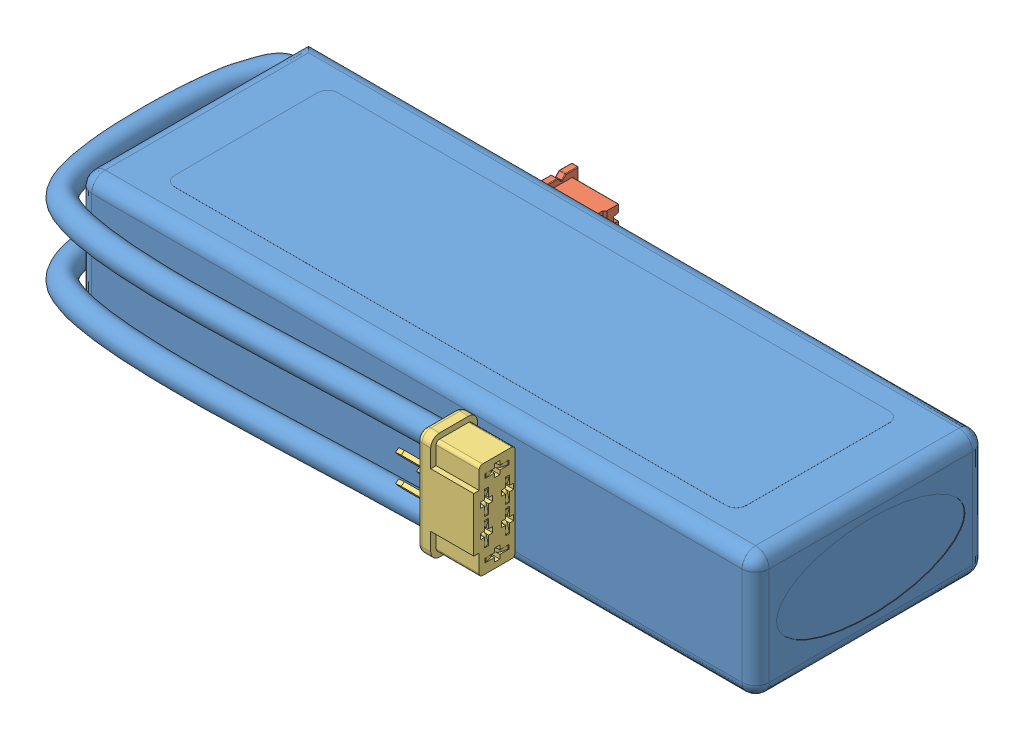
SolidWorks assembly Battery, configuration Default. Lengths in mm.
Overall size (106.54 18.51 46.79).
3 component instances, 3 part files, 4 mates.
Components (placement in the parent):
- Nanotech_1600mAh_3S_Lipo-1: Nanotech_1600mAh_3S_Lipo [Default] at (46.6316 56.8485 77.2715) size (106.54 18.51 44.28)
- Connector JST XHP-4-1: Connector JST XHP-4 [Default] at (30.6082 71.9306 55.2548) x (0 -1 0) z (-1 0 0) size (12.6 5.9 7.84)
- CONNECTOR, MULTIPLEX, PLUG-1: CONNECTOR, MULTIPLEX, PLUG [Default] at (53.5373 66.0779 97.7165) x (0 1 0) z (0 0 -1) size (15.87 13.07 6.89)
Mates (geometry in assembly coordinates):
- Coincident4: coincident anti-aligned: plane of Nanotech_1600mAh_3S_Lipo-1 through (-3.3684 75.3485 60.2715) normal (0 0 -1); plane of Connector JST XHP-4-1 through (30.6082 71.9306 60.2715) normal (0 0 1)
- Coincident5: coincident anti-aligned: plane of Nanotech_1600mAh_3S_Lipo-1 through (-3.3684 75.3485 94.2715) normal (0 0 1); plane of CONNECTOR, MULTIPLEX, PLUG-1 through (61.9173 58.1429 94.2715) normal (0 0 -1)
- Parallel4: parallel aligned: plane of Nanotech_1600mAh_3S_Lipo-1 through (96.6316 56.8485 94.2715) normal (0 -1 0); plane of CONNECTOR, MULTIPLEX, PLUG-1 through (55.5673 58.9429 99.8615) normal (0 -1 0)
- Parallel5: parallel aligned: plane of Nanotech_1600mAh_3S_Lipo-1 through (96.6316 75.3485 94.2715) normal (0 1 0); plane of Connector JST XHP-4-1 through (30.6082 71.9306 55.2548) normal (0 1 0)
